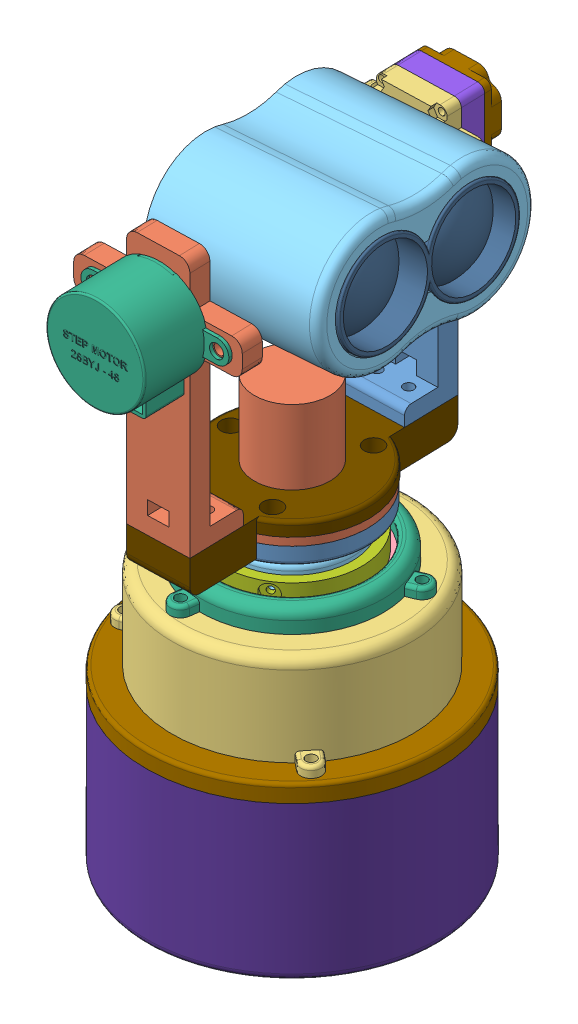
SolidWorks assembly lidar_rotation_stage, configuration Default. Lengths in mm.
Overall size (109.74 187.77 114.6).
32 component instances, 28 part files, 17 mates.
Components (placement in the parent):
- rotating_disk_adptr-1: rotating_disk_adptr [Default] at (66.3001 90.4317 52.9566) x (-0.027776 0 -0.999614) z (0.999614 0 -0.027776) size (44 7.5 44)
- slipring-2: slipring [Default] at (66.3001 100.3317 52.9566) x (0.879579 0 0.475752) z (0.475752 0 -0.879579) size (44 37 44)
- single_bearing-1: single_bearing [Default] at (-7.4084 12.6139 31.7789) x (0.630563 0 -0.776138) z (0.776138 0 0.630563) size (71.47 38 75.8) (flexible)
  - slipring_base-1: slipring_base [Default] at (30.0411 8.7177 70.5618) size (71.47 26.4 75.8)
  - bearing-1: bearing [Default] at (30.0411 61.7177 70.5618) size (47 7 47)
  - rotating_sturt-1: rotating_sturt [Default] at (30.0411 59.8177 70.5618) x (-0.943705 0 -0.330789) z (0.330789 0 -0.943705) size (40.5 18.8 40.5)
  - rotating_disk_strut_secure-1: rotating_disk_strut_secure [Default] at (30.0411 66.2177 70.5618) x (0.999768 0 0.021527) z (-0.021527 0 0.999768) size (56.17 6.5 58.47)
  - lock_disk-2: lock_disk [Default] at (30.0411 60.8177 70.5618) x (-0.943705 0 -0.330789) z (0.330789 0 -0.943705) size (40.5 6 40.5)
  - rotating_disk_gear_adpt v4-1: rotating_disk_gear_adpt v4 [Default] at (30.0411 59.0177 70.5618) x (-0.651878 0 -0.758324) z (0 -1 0) size (40.5 40.5 7)
- motor_encoder_mount-1: motor_encoder_mount [Default] at (47.8355 18.1809 -19.5048) x (0.987437 0 0.158015) z (-0.158015 0 0.987437) size (85 60.72 85) (flexible)
  - gear_plate-1: gear_plate [Default] at (29.6826 29.2508 68.6333) size (85 11 85)
  - motor-1: motor [Default] at (51.2418 -10.7492 54.1006) x (-0.558952 0 -0.8292) z (0.8292 0 -0.558952) size (27.6 49 27.6)
  - S5-X-236-X-S-B-1: S5-X-236-X-S-B [Default] at (22.1087 29.7508 85.6937) x (0.866025 0 -0.5) z (0 -1 0) size (31.05 47.11 36.8)
  - gear2-1: gear2 [Default] at (22.1295 40.2508 54.3019) x (0.137729 0 0.99047) z (0 1 0) size (27 27 9)
  - rod1-1: rod1 [Default] at (38.0033 30.2508 50.3849) size (2 15 2)
  - rod1-2: rod1 [Default] at (22.1295 34.2508 54.3019) x (0.260819 0 0.965388) z (-0.965388 0 0.260819) size (2 15 2)
  - gear1-1: gear1 [Default] at (38.0033 34.2508 50.3849) x (-0.438456 0 -0.898753) z (0 1 0) size (22.68 22.68 10.3)
  - gear0-2: gear0 [Default] at (51.2418 38.0508 54.1006) x (0.478924 0 0.877856) z (0 -1 0) size (6.16 6.16 4.8)
  - gear3 v2-1: gear3 v2 [Default] at (22.1087 47.2692 85.6937) x (0.23793 0 -0.971282) z (0 -1 0) size (20 20 12)
- base_shell-1: base_shell [Default] at (66.3001 2.4317 52.9566) x (-0.356873 0 -0.934153) z (0.934153 0 -0.356873) size (85 45 85)
- rotating_disk-3: rotating_disk [Default] at (-4.6168 68.4808 91.3631) x (-0.027776 0 -0.999614) z (0.999614 0 -0.027776) size (111.27 96.27 63.76) (flexible)
  - rotating_disk_base-1: rotating_disk_base [Default] at (36.4219 21.8509 71.9564) size (80.37 10.47 44.4)
  - rotating_disk_encoder_arm-1: rotating_disk_encoder_arm [Default] at (36.4219 21.8509 71.9564) size (16 65 33)
  - rotating_disk_stepper_arm-1: rotating_disk_stepper_arm [Default] at (36.4219 21.8509 71.9564) size (16 75 47.85)
  - rotating_disk_bearing_holder-1: rotating_disk_bearing_holder [Default] at (66.6873 100.8509 78.7505) size (6 10 33)
  - ball_bearing_lidar-1: ball_bearing_lidar [Default] at (74.4089 100.8509 71.9564) x (0 1 0) z (0 0 1) size (12 3.5 12)
  - SF10 _attachemnt-1: SF10 _attachemnt [Default] at (36.715 147.0899 98.9662) x (-1 0 0) z (0 0.048264 0.998835) size (83.46 38.1 49.67)
  - Step - 28BYJ-48-1: Step - 28BYJ-48 [Varsayılan] at (-22.665 92.8509 71.9564) x (0 0 -1) z (0 -1 0) size (42 28.9 33.48)
  - stepper_encoder-1: stepper_encoder [Default] at (79.195 100.8509 71.9564) x (0 0.998835 -0.048264) z (0 0.048264 0.998835) size (17.8 5 17.8)
  - stepper_encoder_case-1: stepper_encoder_case [Default] at (76.6089 100.8509 71.9564) x (0 0 1) z (0 1 0) size (20 7 26)
  - stepper_encoder_case_cap-1: stepper_encoder_case_cap [Default] at (83.6089 100.8509 71.9564) x (0 -1 0) z (0 0 1) size (26 5 20)
  - sf30c-2: sf30c [Default] at (36.715 101.1298 74.7041) x (1 0 0) z (0 -0.048264 -0.998835) size (57.98 31.85 50.31)
Mates (geometry in assembly coordinates):
- Concentric41: concentric aligned: circle of rotating_disk_adptr-1; cylinder of slipring-2 through (75.4677 97.9317 67.8631) axis (0 1 0) radius 2.75
- Concentric42: concentric anti-aligned: circle of rotating_disk_adptr-1; circle of slipring-2
- Coincident27: coincident anti-aligned: plane of rotating_disk_adptr-1 through (66.3001 97.9317 52.9566) normal (0 1 0); plane of slipring-2 through (66.3001 97.9317 52.9566) normal (0 -1 0)
- Concentric44: concentric anti-aligned: cylinder of rotating_disk_adptr-1 through (61.0668 97.9317 62.6319) axis (0 -1 0) radius 1; cylinder of single_bearing-1/rotating_sturt-1 through (61.0668 80.4317 62.6319) axis (0 1 0) radius 1
- Concentric45: concentric anti-aligned: cylinder of rotating_disk_adptr-1 through (66.3001 97.9317 52.9566) axis (0 -1 0) radius 7.5; cylinder of single_bearing-1/rotating_sturt-1 through (66.3001 87.4317 52.9566) axis (0 1 0) radius 8
- Coincident30: coincident anti-aligned: plane of rotating_disk_adptr-1 through (66.3001 90.4317 52.9566) normal (0 -1 0); plane of single_bearing-1/rotating_sturt-1 through (66.3001 90.4317 52.9566) normal (0 1 0)
- Coincident31: coincident anti-aligned: plane of single_bearing-1/slipring_base-1 through (182.0521 52.4317 27.1737) normal (0 -1 0); plane of motor_encoder_mount-1/gear_plate-1 through (66.3001 52.4317 52.9566) normal (0 1 0)
- Concentric46: concentric anti-aligned: circle of single_bearing-1/slipring_base-1; cylinder of motor_encoder_mount-1/gear_plate-1 through (66.3001 52.4317 52.9566) axis (0 -1 0) radius 42.5
- Concentric47: concentric anti-aligned: cylinder of single_bearing-1/slipring_base-1 through (30.9891 55.4317 66.4464) axis (0 -1 0) radius 1.5; cylinder of motor_encoder_mount-1/gear_plate-1 through (30.9891 54.6317 66.4464) axis (0 1 0) radius 1.5
- GearMate1: gear = 14 : 28 mm: axis of single_bearing-1/rotating_disk_gear_adpt v4-1 through (66.3001 64.6317 52.9566) axis (0 1 0); line of motor_encoder_mount-1/gearv3 v1-1 through (60.4593 64.9501 65.68) axis (0 1 0)
- GearMate3: gear = 21 : 28 mm: line of single_bearing-1/rotating_disk_gear_adpt v4-1 through (66.3001 64.6317 52.9566) axis (0 1 0); line of motor_encoder_mount-1/gear2-1 through (61.1065 67.4317 37.6117) axis (0 -1 0)
- GearMate8: gear = 1 : 1 mm: line of single_bearing-1/rotating_disk_gear_adpt v4-1 through (66.3001 64.6317 52.9566) axis (0 1 0); line of motor_encoder_mount-1/gear3 v2-1 through (56.1255 55.4501 68.6058) axis (0 1 0)
- Tangent1: tangent aligned: cylinder of slipring-2 through (48.8069 97.9317 53.4427) axis (0 1 0) radius 2.75; cylinder of rotating_disk-3/rotating_disk_base-1 through (48.8069 100.3317 53.4427) axis (0 1 0) radius 2.75
- Concentric52: concentric anti-aligned: cylinder of slipring-2 through (66.3001 125.9317 52.9566) axis (0 -1 0) radius 11; cylinder of rotating_disk-3/rotating_disk_base-1 through (66.3001 100.3317 52.9566) axis (0 1 0) radius 11
- Coincident42: coincident anti-aligned: plane of slipring-2 through (66.3001 100.3317 52.9566) normal (0 1 0); plane of rotating_disk-3/rotating_disk_base-1 through (66.3001 100.3317 52.9566) normal (0 -1 0)
- Coincident46: coincident aligned: circle of motor_encoder_mount-1/gear_plate-1; circle of base_shell-1
- Concentric55: concentric aligned: circle of single_bearing-1/slipring_base-1; circle of base_shell-1
